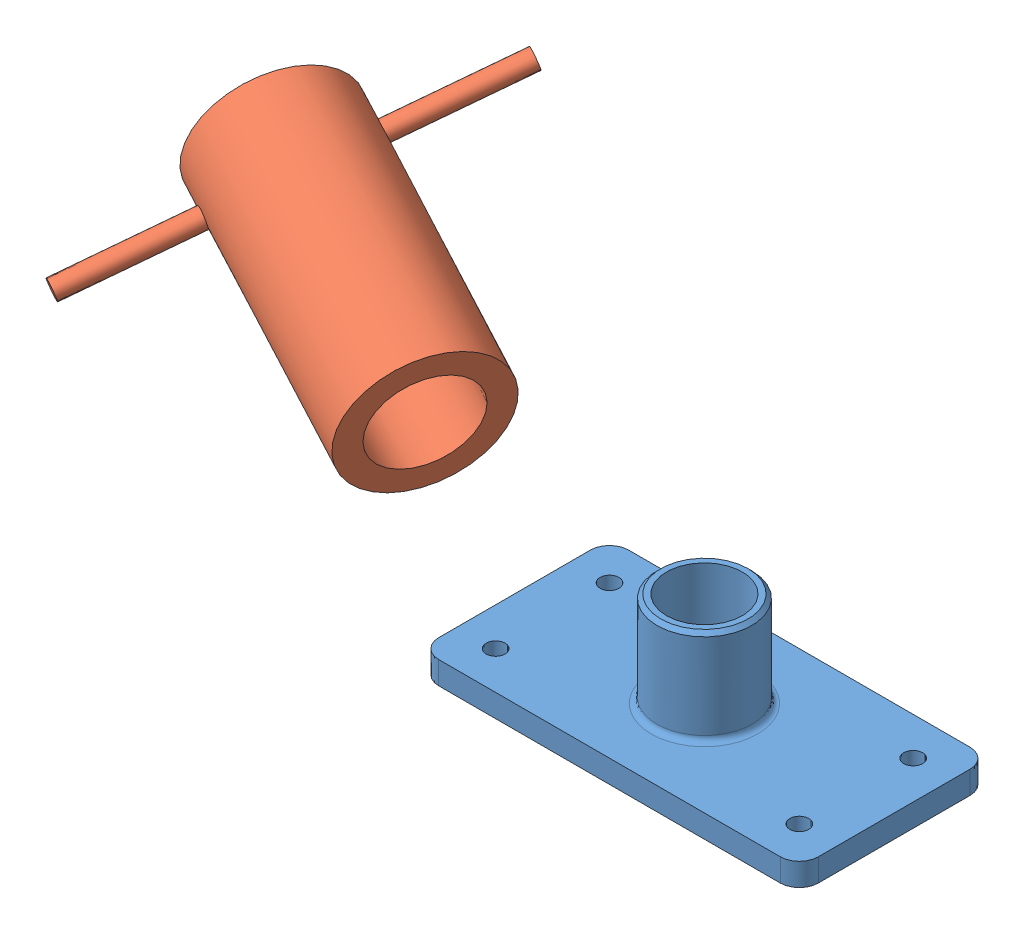
SolidWorks assembly Assem1, configuration Default. Lengths in mm.
Overall size (430.14 168.64 253.13).
2 component instances, 2 part files, 0 mates.
Components (placement in the parent):
- Pipe Base Plate-1: Pipe Base Plate [Default] at (-99.3641 -48.3601 64.2273) size (200 62 100)
- Handle-1: Handle [Default] at (-315.9943 34.3146 34.8196) x (0.899444 -0.238967 0.365916) z (-0.428749 -0.32022 0.844768) size (150 75 200)
